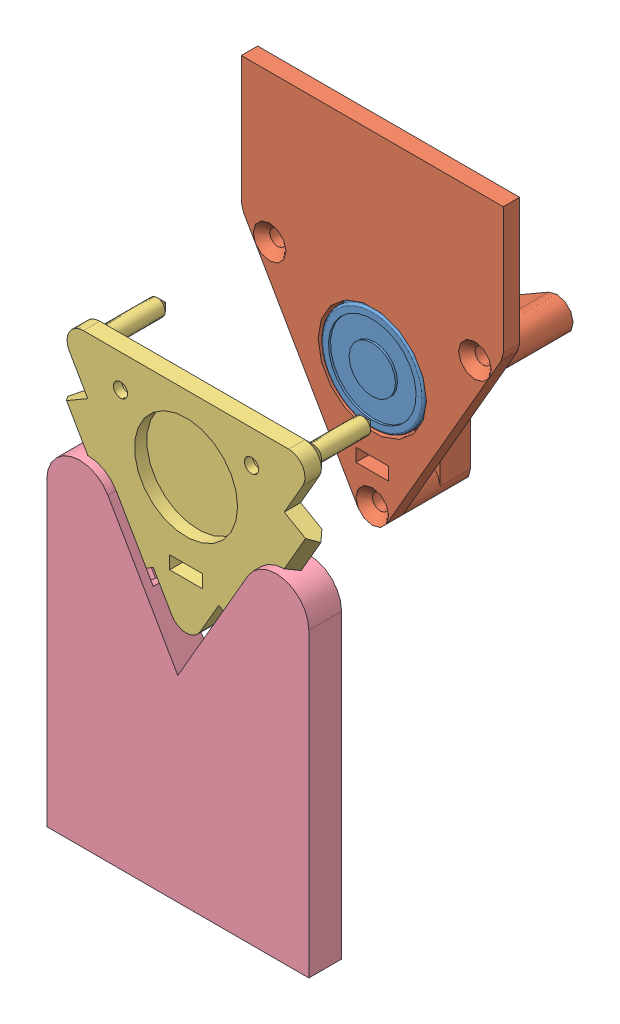
SolidWorks assembly Assem1, configuration Default. Lengths in mm.
Overall size (101.6 221.34 107.15).
4 component instances, 4 part files, 10 mates.
Components (placement in the parent):
- 25kg electromagnet-1: 25kg electromagnet [Default] at (0 0 3.175) x (1 0 0) z (0 1 0) size (40 20 40)
- ATC-1: ATC [Default] at origin size (101.6 132.44 31.75)
- ATC Tool Mount-1: ATC Tool Mount [Default] at (0 0 72.2295) size (98.2 81.64 31.75)
- ATC Tool Holder-1: ATC Tool Holder [Default] at (0 -65.0088 72.2295) size (101.6 129.49 12.7)
Mates (geometry in assembly coordinates):
- Coincident1: coincident aligned: plane of ATC-1 through (0 0 0) normal (0 0 1)
- Coincident2: coincident aligned: plane of ATC-1 through (0 0 0) normal (0 1 0)
- Coincident3: coincident aligned: plane of ATC-1 through (0 0 0) normal (1 0 0)
- Coincident4: coincident anti-aligned: plane of 25kg electromagnet-1 through (0 0 -16.825) normal (0 0 -1); plane of ATC-1 through (0 0 -16.825) normal (0 0 1)
- Concentric1: concentric aligned: cylinder of 25kg electromagnet-1 through (0 0 -16.825) axis (0 0 1) radius 20; cylinder of ATC-1 through (0 0 -3.175) axis (0 0 1) radius 21
- Concentric2: concentric aligned: cylinder of ATC-1 through (-39.8015 22.9794 -22.225) axis (0 0 1) radius 3.175; cylinder of ATC Tool Mount-1 through (-39.8015 22.9794 43.6545) axis (0 0 1) radius 3.175
- Concentric3: concentric aligned: cylinder of ATC-1 through (39.8015 22.9794 -22.225) axis (0 0 1) radius 3.175; cylinder of ATC Tool Mount-1 through (39.8015 22.9794 43.6545) axis (0 0 1) radius 3.175
- Coincident6: coincident anti-aligned: plane of ATC Tool Mount-1 through (0 0 69.0545) normal (0 0 -1); plane of ATC Tool Holder-1 through (-18.1993 -46.1867 69.0545) normal (0 0 1)
- Coincident7: coincident aligned: plane of ATC Tool Mount-1 through (0 0 72.2295) normal (1 0 0); plane of ATC Tool Holder-1 through (0 -65.0088 72.2295) normal (1 0 0)
- Coincident8: coincident anti-aligned: plane of ATC Tool Mount-1 through (-49.0985 0.9823 72.2295) normal (-0.612372 -0.353553 -0.707107); plane of ATC Tool Holder-1 through (-20.9489 -47.7742 72.2295) normal (0.612372 0.353553 0.707107)
